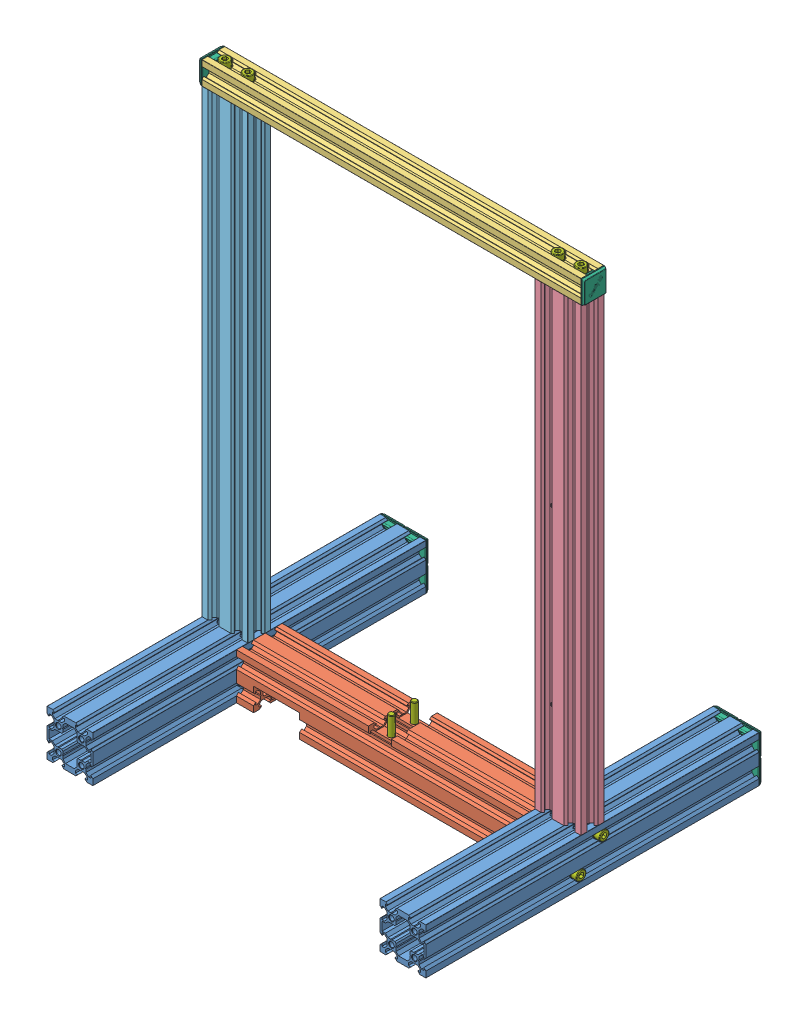
SolidWorks assembly ASM Frame, configuration Standard. Lengths in mm.
Overall size (343.61 468.87 295.49).
30 component instances, 7 part files, 57 mates.
Components (placement in the parent):
- 4040 profile-1: 4040 profile [Standard] at (155 30 -145) x (0 0 1) z (0 -1 0) size (290 40 40)
- 4040 profile-2: 4040 profile [Standard] at (-135 30 -145) x (0 0 1) z (0 -1 0) size (290 40 40)
- 4040-3 profile-1: 4040-3 profile [Standard] at (-125 10 -10) size (250 40 40)
- 2020-2 profile-1: 2020-2 profile [Standard] at (-165 450 0) size (330 20 20)
- 2040-3R profile-1: 2040-3R profile [Standard] at (135 370 0) x (0 -1 0) z (1 0 0) size (400 20 40)
- 2040-3L profile-1: 2040-3L profile [Standard] at (-135 370 0) x (0 -1 0) z (-1 0 0) size (400 20 40)
- 2020 Endcap-1: 2020 Endcap [Standard] at (168 450 0) x (0 1 0) z (-1 0 0) size (28.07 28.13 10.79)
- 2020 Endcap-2: 2020 Endcap [Standard] at (-168 450 0) x (0 1 0) z (1 0 0) size (28.07 28.13 10.79)
- 2020 Endcap-3: 2020 Endcap [Standard] at (155 30 -148) x (0 1 0) z (0 0 1) size (28.07 28.13 10.79)
- 2020 Endcap-4: 2020 Endcap [Standard] at (-135 30 -148) x (0 1 0) z (0 0 1) size (28.07 28.13 10.79)
- M5X45 Socket Head Screw-1: M5X45 Socket Head Screw [Standard] at (160.4 30 -10) x (-1 0 0) z (0 0.226621 0.973983) size (50.2 8.6 8.58)
- M5X45 Socket Head Screw-2: M5X45 Socket Head Screw [Standard] at (160.4 10 10) x (-1 0 0) z (0 0.069327 0.997594) size (50.2 8.6 8.58)
- M5X45 Socket Head Screw-3: M5X45 Socket Head Screw [Standard] at (-160.2 30 -10) x (1 0 0) z (0 -0.819975 -0.572399) size (50.2 8.6 8.58)
- M5X45 Socket Head Screw-4: M5X45 Socket Head Screw [Standard] at (-160.2 10 10) x (1 0 0) z (0 0.266862 -0.963735) size (50.2 8.6 8.58)
- M5X45 Socket Head Screw-5: M5X45 Socket Head Screw [Standard] at (155 4.6 0) x (0 1 0) z (0.615355 0 -0.78825) size (50.2 8.6 8.58)
- M5X45 Socket Head Screw-6: M5X45 Socket Head Screw [Standard] at (-135 4.6 0) x (0 1 0) z (0.246463 0 0.969152) size (50.2 8.6 8.58)
- M5X45 Socket Head Screw-7: M5X45 Socket Head Screw [Standard] at (-155 4.6 0) x (0 1 0) z (0.981565 0 -0.191131) size (50.2 8.6 8.58)
- M5X45 Socket Head Screw-8: M5X45 Socket Head Screw [Standard] at (135 4.6 0) x (0 1 0) z (0.780912 0 -0.624641) size (50.2 8.6 8.58)
- M5X45 Socket Head Screw-9: M5X45 Socket Head Screw [Standard] at (0 4.2 10) x (0 1 0) z (-0.952023 0 -0.306028) size (50.2 8.6 8.58)
- M5X45 Socket Head Screw-10: M5X45 Socket Head Screw [Standard] at (0 4.2 -10) x (0 1 0) z (-0.011222 0 -0.999937) size (50.2 8.6 8.58)
- M5X45 Socket Head Screw-11: M5X45 Socket Head Screw [Standard] at (155 455.8 0) x (0 -1 0) z (-0.999945 0 0.010518) size (50.2 8.6 8.58)
- M5X45 Socket Head Screw-12: M5X45 Socket Head Screw [Standard] at (135 455.8 0) x (0 -1 0) z (-0.945615 0 -0.325289) size (50.2 8.6 8.58)
- M5X45 Socket Head Screw-13: M5X45 Socket Head Screw [Standard] at (-155 455.8 0) x (0 -1 0) z (0.161435 0 -0.986883) size (50.2 8.6 8.58)
- M5X45 Socket Head Screw-14: M5X45 Socket Head Screw [Standard] at (-135 455.8 0) x (0 -1 0) z (0.161435 0 -0.986883) size (50.2 8.6 8.58)
- 2020 Endcap-5: 2020 Endcap [Standard] at (-135 10 -148) x (0 1 0) z (0 0 1) size (28.07 28.13 10.79)
- 2020 Endcap-6: 2020 Endcap [Standard] at (-155 30 -148) x (0 1 0) z (0 0 1) size (28.07 28.13 10.79)
- 2020 Endcap-7: 2020 Endcap [Standard] at (-155 10 -148) x (0 1 0) z (0 0 1) size (28.07 28.13 10.79)
- 2020 Endcap-8: 2020 Endcap [Standard] at (155 10 -148) x (0 1 0) z (0 0 1) size (28.07 28.13 10.79)
- 2020 Endcap-9: 2020 Endcap [Standard] at (135 30 -148) x (0 1 0) z (0 0 1) size (28.07 28.13 10.79)
- 2020 Endcap-10: 2020 Endcap [Standard] at (135 10 -148) x (0 1 0) z (0 0 1) size (28.07 28.13 10.79)
Mates (geometry in assembly coordinates):
- Deckungsgleich35: coincident anti-aligned: plane of 4040 profile-1 through (125 20 145) normal (-1 0 0); plane of 4040-3 profile-1 through (125 39.8 -30) normal (1 0 0)
- Deckungsgleich41: coincident anti-aligned: plane of 4040 profile-1 through (159.2 30 -7.4) normal (1 0 0); plane of M5X45 Socket Head Screw-1 through (159.2 30 -10) normal (-1 0 0)
- Deckungsgleich42: coincident anti-aligned: plane of 4040 profile-1 through (159.2 10 12.6) normal (1 0 0); plane of M5X45 Socket Head Screw-2 through (159.2 10 10) normal (-1 0 0)
- Deckungsgleich45: coincident anti-aligned: plane of 4040 profile-1 through (155 5.8 2.6) normal (0 -1 0); plane of M5X45 Socket Head Screw-5 through (155 5.8 0) normal (0 1 0)
- Deckungsgleich48: coincident anti-aligned: plane of 4040 profile-1 through (135 5.8 2.6) normal (0 -1 0); plane of M5X45 Socket Head Screw-8 through (135 5.8 0) normal (0 1 0)
- Deckungsgleich73: coincident anti-aligned: plane of 4040 profile-1 through (145 40 145) normal (0 1 0); plane of 2040-3R profile-1 through (135 40 0) normal (0 -1 0)
- Konzentrisch59: concentric anti-aligned: cylinder of 4040 profile-1 through (125 10 10) axis (-1 0 0) radius 2.65; cylinder of M5X45 Socket Head Screw-2 through (161.577 10 10) axis (1 0 0) radius 2.5
- Konzentrisch60: concentric anti-aligned: cylinder of 4040 profile-1 through (125 30 -10) axis (-1 0 0) radius 2.65; cylinder of M5X45 Socket Head Screw-1 through (161.577 30 -10) axis (1 0 0) radius 2.5
- Konzentrisch63: concentric anti-aligned: cylinder of 4040 profile-1 through (155 40 0) axis (0 1 0) radius 2.65; cylinder of M5X45 Socket Head Screw-5 through (155 3.423 0) axis (0 -1 0) radius 2.5
- Konzentrisch64: concentric anti-aligned: cylinder of 4040 profile-1 through (135 40 0) axis (0 1 0) radius 2.65; cylinder of M5X45 Socket Head Screw-8 through (135 3.423 0) axis (0 -1 0) radius 2.5
- Deckungsgleich130: coincident aligned: plane of 4040 profile-1 through (145 40 145) normal (0 1 0); plane of 2020 Endcap-3 through (164.8 40 -145) normal (0 1 0)
- Deckungsgleich131: coincident aligned: plane of 4040 profile-1 through (165 20 145) normal (1 0 0); plane of 2020 Endcap-3 through (165 20.2 -145) normal (1 0 0)
- Deckungsgleich132: coincident anti-aligned: plane of 4040 profile-1 through (155 30 -145) normal (0 0 -1); plane of 2020 Endcap-3 through (164.8 20.2 -145) normal (0 0 1)
- Deckungsgleich36: coincident anti-aligned: plane of 4040 profile-2 through (-125 20 145) normal (1 0 0); plane of 4040-3 profile-1 through (-125 10 -10) normal (-1 0 0)
- Deckungsgleich43: coincident anti-aligned: plane of 4040 profile-2 through (-159 33.0101 145) normal (-1 0 0); plane of M5X45 Socket Head Screw-3 through (-159 30 -10) normal (1 0 0)
- Deckungsgleich44: coincident anti-aligned: plane of 4040 profile-2 through (-159 6.9899 145) normal (-1 0 0); plane of M5X45 Socket Head Screw-4 through (-159 10 10) normal (1 0 0)
- Deckungsgleich46: coincident anti-aligned: plane of 4040 profile-2 through (-135 5.8 2.6) normal (0 -1 0); plane of M5X45 Socket Head Screw-6 through (-135 5.8 0) normal (0 1 0)
- Deckungsgleich47: coincident anti-aligned: plane of 4040 profile-2 through (-155 5.8 2.6) normal (0 -1 0); plane of M5X45 Socket Head Screw-7 through (-155 5.8 0) normal (0 1 0)
- Konzentrisch56: concentric anti-aligned: cylinder of 4040 profile-2 through (-155 40 0) axis (0 1 0) radius 2.65; cylinder of M5X45 Socket Head Screw-7 through (-155 3.423 0) axis (0 -1 0) radius 2.5
- Konzentrisch57: concentric aligned: cylinder of 4040 profile-2 through (-165 30 -10) axis (-1 0 0) radius 2.65; cylinder of M5X45 Socket Head Screw-3 through (-161.377 30 -10) axis (-1 0 0) radius 2.5
- Konzentrisch58: concentric aligned: cylinder of 4040 profile-2 through (-165 10 10) axis (-1 0 0) radius 2.65; cylinder of M5X45 Socket Head Screw-4 through (-161.377 10 10) axis (-1 0 0) radius 2.5
- Konzentrisch65: concentric anti-aligned: cylinder of 4040 profile-2 through (-135 40 0) axis (0 1 0) radius 2.65; cylinder of M5X45 Socket Head Screw-6 through (-135 3.423 0) axis (0 -1 0) radius 2.5
- Deckungsgleich133: coincident aligned: plane of 4040 profile-2 through (-145 40 145) normal (0 1 0); plane of 2020 Endcap-4 through (-125.2 40 -145) normal (0 1 0)
- Deckungsgleich134: coincident aligned: plane of 4040 profile-2 through (-125 20 145) normal (1 0 0); plane of 2020 Endcap-4 through (-125 20.2 -145) normal (1 0 0)
- Deckungsgleich135: coincident anti-aligned: plane of 4040 profile-2 through (-135 30 -145) normal (0 0 -1); plane of 2020 Endcap-4 through (-125.2 20.2 -145) normal (0 0 1)
- Deckungsgleich150: coincident anti-aligned: plane of 4040 profile-2 through (-145 40 145) normal (0 1 0); plane of 2040-3L profile-1 through (-135 40 0) normal (0 -1 0)
- Konzentrisch51: concentric aligned: cylinder of 2040-3R profile-1 through (155 40 0) axis (0 1 0) radius 2; cylinder of 2020-2 profile-1 through (155 460 0) axis (0 1 0) radius 2.65
- Konzentrisch52: concentric anti-aligned: cylinder of 2040-3R profile-1 through (135 40 0) axis (0 1 0) radius 2; cylinder of M5X45 Socket Head Screw-8 through (135 3.423 0) axis (0 -1 0) radius 2.5
- Deckungsgleich75: coincident anti-aligned: plane of 2040-3R profile-1 through (135 440 0) normal (0 1 0); plane of 2020-2 profile-1 through (180 440 10) normal (0 -1 0)
- Konzentrisch62: concentric anti-aligned: cylinder of 2040-3R profile-1 through (155 40 0) axis (0 1 0) radius 2; cylinder of M5X45 Socket Head Screw-5 through (155 3.423 0) axis (0 -1 0) radius 2.5
- Konzentrisch61: concentric anti-aligned: cylinder of M5X45 Socket Head Screw-1 through (161.577 30 -10) axis (1 0 0) radius 2.5; cylinder of 4040-3 profile-1 through (165 30 -10) axis (-1 0 0) radius 2
- Konzentrisch38: concentric aligned: cylinder of 4040-3 profile-1 through (0 0 10) axis (0 -1 0) radius 2.65; cylinder of M5X45 Socket Head Screw-9 through (0 3.023 10) axis (0 -1 0) radius 2.5
- Deckungsgleich49: coincident anti-aligned: plane of 4040-3 profile-1 through (2.65 5.4 10) normal (0 -1 0); plane of M5X45 Socket Head Screw-9 through (0 5.4 10) normal (0 1 0)
- Konzentrisch39: concentric aligned: cylinder of 4040-3 profile-1 through (0 0 -10) axis (0 -1 0) radius 2.65; cylinder of M5X45 Socket Head Screw-10 through (0 3.023 -10) axis (0 -1 0) radius 2.5
- Deckungsgleich50: coincident anti-aligned: plane of 4040-3 profile-1 through (2.65 5.4 -10) normal (0 -1 0); plane of M5X45 Socket Head Screw-10 through (0 5.4 -10) normal (0 1 0)
- Konzentrisch129: concentric anti-aligned: cylinder of 2040-3L profile-1 through (-135 40 0) axis (0 1 0) radius 2; cylinder of M5X45 Socket Head Screw-6 through (-135 3.423 0) axis (0 -1 0) radius 2.5
- Konzentrisch128: concentric anti-aligned: cylinder of 2040-3L profile-1 through (-155 40 0) axis (0 1 0) radius 2; cylinder of M5X45 Socket Head Screw-7 through (-155 3.423 0) axis (0 -1 0) radius 2.5
- Deckungsgleich58: coincident aligned: plane of 2020-2 profile-1 through (180 460 10) normal (0 1 0); plane of 2020 Endcap-1 through (165 460 9.8) normal (0 1 0)
- Deckungsgleich59: coincident aligned: plane of 2020-2 profile-1 through (180 460 10) normal (0 0 1); plane of 2020 Endcap-1 through (165 440.2 10) normal (0 0 1)
- Deckungsgleich60: coincident anti-aligned: plane of 2020-2 profile-1 through (165 460 -10) normal (1 0 0); plane of 2020 Endcap-1 through (165 440.2 9.8) normal (-1 0 0)
- Deckungsgleich61: coincident aligned: plane of 2020-2 profile-1 through (180 460 10) normal (0 1 0); plane of 2020 Endcap-2 through (-165 460 -9.8) normal (0 1 0)
- Deckungsgleich62: coincident aligned: plane of 2020-2 profile-1 through (180 460 -10) normal (0 0 -1); plane of 2020 Endcap-2 through (-165 440.2 -10) normal (0 0 -1)
- Deckungsgleich63: coincident anti-aligned: plane of 2020-2 profile-1 through (-165 450 0) normal (-1 0 0); plane of 2020 Endcap-2 through (-165 440.2 -9.8) normal (1 0 0)
- Konzentrisch80: concentric aligned: cylinder of 2020-2 profile-1 through (155 460 0) axis (0 1 0) radius 2.65; cylinder of M5X45 Socket Head Screw-11 through (155 456.977 0) axis (0 1 0) radius 2.5
- Deckungsgleich90: coincident anti-aligned: plane of 2020-2 profile-1 through (157.65 454.6 0) normal (0 1 0); plane of M5X45 Socket Head Screw-11 through (155 454.6 0) normal (0 -1 0)
- Konzentrisch81: concentric aligned: cylinder of 2020-2 profile-1 through (135 460 0) axis (0 1 0) radius 2.65; cylinder of M5X45 Socket Head Screw-12 through (135 456.977 0) axis (0 1 0) radius 2.5
- Deckungsgleich91: coincident anti-aligned: plane of 2020-2 profile-1 through (137.65 454.6 0) normal (0 1 0); plane of M5X45 Socket Head Screw-12 through (135 454.6 0) normal (0 -1 0)
- Konzentrisch82: concentric aligned: cylinder of 2020-2 profile-1 through (-155 460 0) axis (0 1 0) radius 2.65; cylinder of M5X45 Socket Head Screw-13 through (-155 456.977 0) axis (0 1 0) radius 2.5
- Deckungsgleich92: coincident anti-aligned: plane of 2020-2 profile-1 through (-152.35 454.6 0) normal (0 1 0); plane of M5X45 Socket Head Screw-13 through (-155 454.6 0) normal (0 -1 0)
- Konzentrisch83: concentric aligned: cylinder of 2020-2 profile-1 through (-135 460 0) axis (0 1 0) radius 2.65; cylinder of M5X45 Socket Head Screw-14 through (-135 456.977 0) axis (0 1 0) radius 2.5
- Deckungsgleich93: coincident anti-aligned: plane of 2020-2 profile-1 through (-132.35 454.6 0) normal (0 1 0); plane of M5X45 Socket Head Screw-14 through (-135 454.6 0) normal (0 -1 0)
- Konzentrisch130: concentric aligned: cylinder of 2040-3L profile-1 through (-155 40 0) axis (0 1 0) radius 2; cylinder of 2020-2 profile-1 through (-155 460 0) axis (0 1 0) radius 2.65
- Deckungsgleich151: coincident anti-aligned: plane of 2040-3L profile-1 through (-135 440 0) normal (0 1 0); plane of 2020-2 profile-1 through (180 440 10) normal (0 -1 0)
- Konzentrisch131: concentric aligned: cylinder of 4040-3 profile-1 through (165 10 10) axis (-1 0 0) radius 2; cylinder of M5X45 Socket Head Screw-4 through (-161.377 10 10) axis (-1 0 0) radius 2.5
- Deckungsgleich152: coincident aligned: plane of 4040-3 profile-1 through (0 10 -10) normal (1 0 0); plane of assembly through (0 0 0) normal (1 0 0)
- Deckungsgleich153: coincident anti-aligned: plane of 4040-3 profile-1 through (165 0 0) normal (0 -1 0); plane of assembly through (0 0 0) normal (0 1 0)
- Deckungsgleich154: coincident aligned: plane of 2040-3L profile-1; plane of assembly through (0 0 0) normal (0 0 1)
